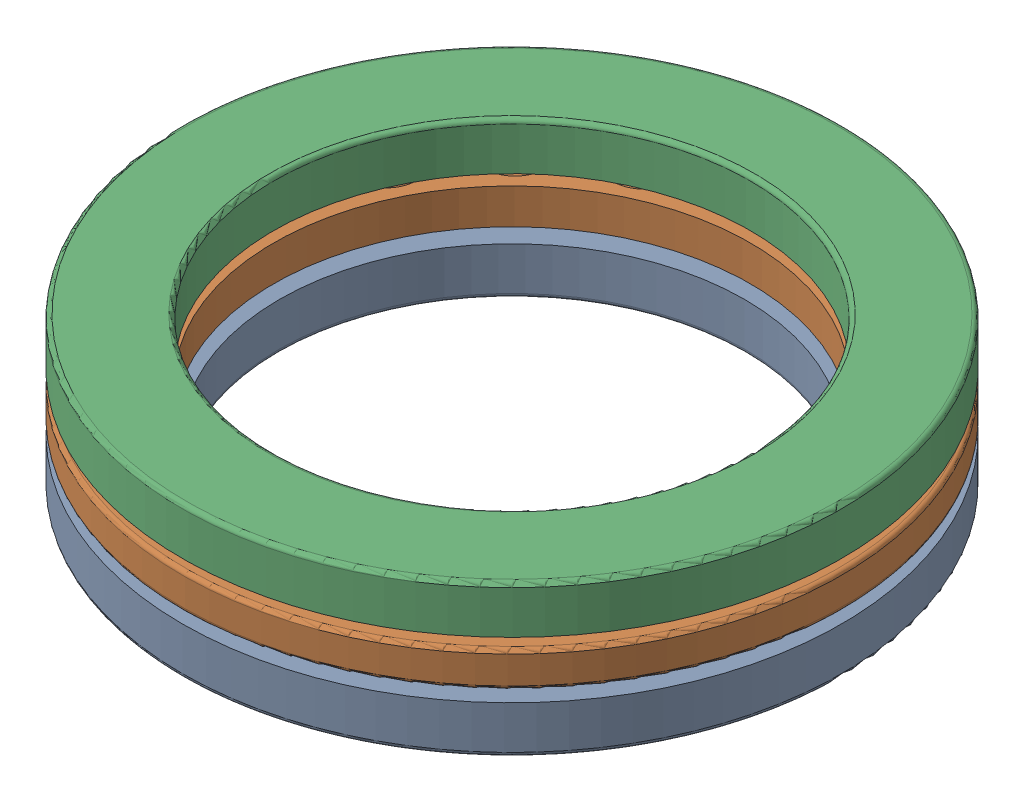
SolidWorks assembly SKF 51224, configuration Default. Lengths in mm.
Overall size (190.86 39 190.86).
3 component instances, 3 part files, 4 mates.
Components (placement in the parent):
- 51224_bottom-1: 51224_bottom [Default] at (55.1145 86.7365 118.9699) x (1 0 0) z (0 0 -1) size (170 12.2 170)
- 51224_middle-1: 51224_middle [Default] at (55.1145 89.474 118.9699) x (0.991331 0 0.131388) z (-0.131388 0 0.991331) size (170 18.26 170)
- 51224_top-1: 51224_top [Default] at (55.1145 101.3415 118.9699) x (0.999827 0 -0.018578) z (0.018578 0 0.999827) size (170 12.2 170)
Mates (geometry in assembly coordinates):
- Concentric1: concentric: cylinder of 51224_bottom-1 through (55.1145 74.5365 118.9699) axis (0 1 0) radius 85; cylinder of 51224_middle-1 through (55.1145 98.604 118.9699) axis (0 -1 0) radius 85
- Tangent1: tangent: torus of 51224_bottom-1; sphere of 51224_middle-1
- Concentric2: concentric: cylinder of 51224_middle-1 through (55.1145 98.604 118.9699) axis (0 -1 0) radius 85; cylinder of 51224_top-1 through (55.1145 113.5415 118.9699) axis (0 -1 0) radius 85
- Tangent2: tangent: torus of 51224_top-1; sphere of 51224_middle-1
